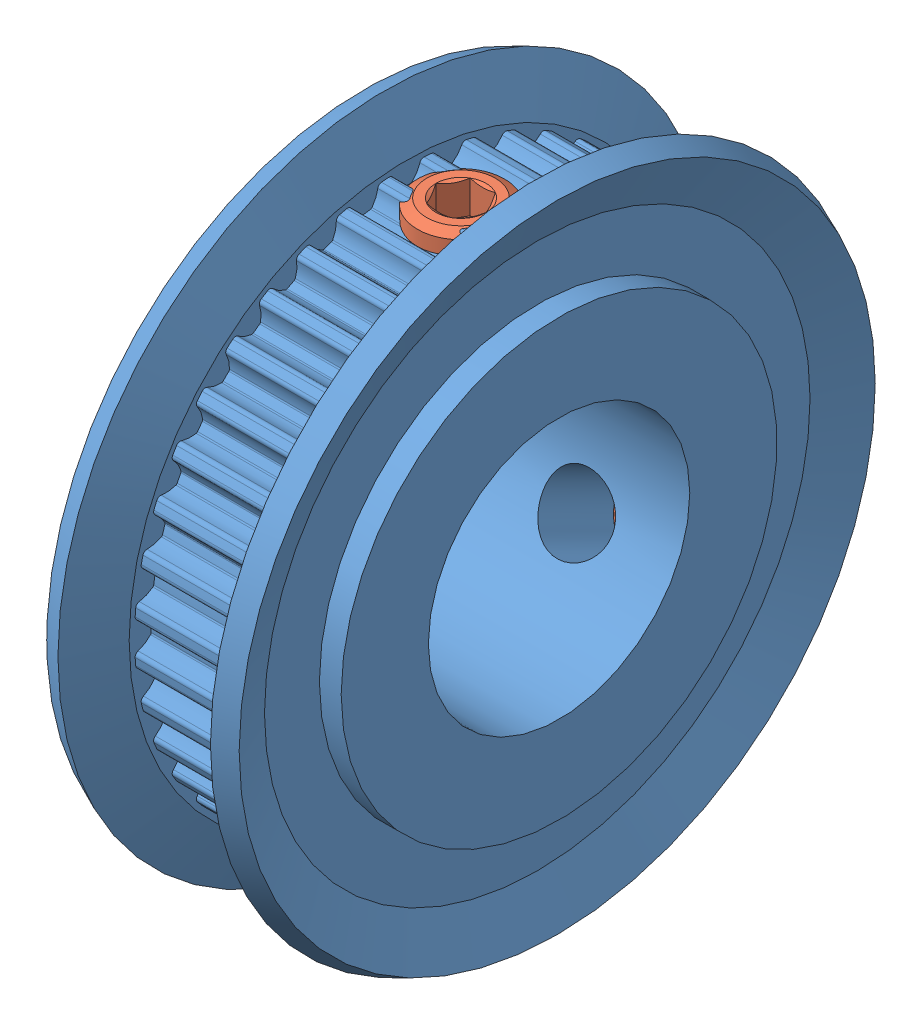
SolidWorks assembly Assem2, configuration Default. Lengths in mm.
Overall size (10.5 30 30).
3 component instances, 2 part files, 0 mates.
Components (placement in the parent):
- HTPK40S2M040_A_P12_a-1: HTPK40S2M040_A_P12_a [Default] at origin size (9 30 30)
- Gewindestift_DIN_913___M4x3_-1: Gewindestift_DIN_913___M4x3_ [Default] at (4.5 12.48 0) x (0 -1 0) z (-1 0 0) size (3 4 4)
- Gewindestift_DIN_913___M4x3_-2: Gewindestift_DIN_913___M4x3_ [Default] at (4.5 -5.6658 -11.1198) x (0 0.45399 0.891007) z (-1 0 0) size (3 4 4)
